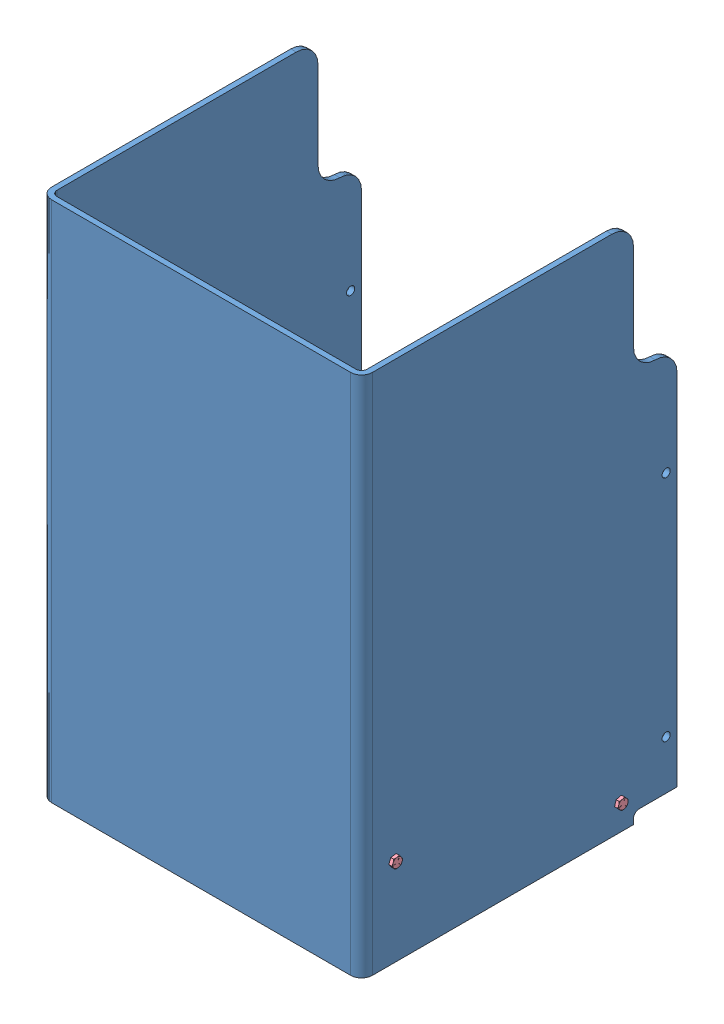
SolidWorks assembly GE-19143, configuration Default. Lengths in mm.
Overall size (382.59 609.6 368.3).
8 component instances, 4 part files, 16 mates.
Components (placement in the parent):
- GE-19144-1: GE-19144 [Default] at origin size (374.65 609.6 368.3)
- GE-19145-3: GE-19145 [Default] at (311.15 103.4321 330.2) x (0 0 1) z (-1 0 0) size (14.66 12.7 361.95)
- GE-19145-4: GE-19145 [Default] at (311.15 30.737 66.675) x (0 -0.158553 0.987351) z (-1 0 0) size (14.66 12.7 361.95)
- GE-19146-1: GE-19146 [Default] at (7.9375 21.7341 10.16) x (0 0.265924 0.963994) z (-1 0 0) size (358.78 3.17 358.78)
- hex_.25_20_.75-1: hex_.25_20_.75 [hex_.25_20_.75] at (7.5406 30.737 66.675) size (23.02 12.83 11.11)
- hex_.25_20_.75-2: hex_.25_20_.75 [hex_.25_20_.75] at (7.5406 103.4321 330.2) x (1 0 0) z (0 -0.158553 0.987351) size (23.02 12.83 11.11)
- hex_.25_20_.75-4: hex_.25_20_.75 [hex_.25_20_.75] at (367.1094 30.737 66.675) x (-1 0 0) z (0 -0.282984 -0.959125) size (23.02 12.83 11.11)
- hex_.25_20_.75-6: hex_.25_20_.75 [hex_.25_20_.75] at (367.1094 103.4321 330.2) x (-1 0 0) z (0 -0.371154 -0.928571) size (23.02 12.83 11.11)
Mates (geometry in assembly coordinates):
- Distance1: distance = 1.5875 mm: plane of GE-19146-1 through (366.7125 24.7948 9.3157) normal (1 0 0); plane of GE-19144-1 through (368.3 609.6 0) normal (-1 0 0)
- Concentric3: concentric: cylinder of GE-19144-1 through (0 30.737 66.675) axis (1 0 0) radius 3.3782; cylinder of hex_.25_20_.75-1 through (0 30.737 66.675) axis (1 0 0) radius 3.175
- Coincident8: coincident: plane of GE-19144-1 through (0 609.6 0) normal (-1 0 0); plane of hex_.25_20_.75-1 through (0 33.9449 72.2313) normal (1 0 0)
- Concentric4: concentric: cylinder of GE-19144-1 through (0 103.4321 330.2) axis (1 0 0) radius 3.3782; cylinder of hex_.25_20_.75-2 through (0 103.4321 330.2) axis (1 0 0) radius 3.175
- Coincident9: coincident: plane of GE-19144-1 through (0 609.6 0) normal (-1 0 0); plane of hex_.25_20_.75-2 through (0 105.7184 336.1946) normal (1 0 0)
- Concentric5: concentric: cylinder of GE-19144-1 through (0 30.737 66.675) axis (1 0 0) radius 3.3782; cylinder of hex_.25_20_.75-4 through (374.65 30.737 66.675) axis (-1 0 0) radius 3.175
- Coincident10: coincident: plane of GE-19144-1 through (374.65 609.6 368.3) normal (1 0 0); plane of hex_.25_20_.75-4 through (374.65 32.2414 60.4381) normal (-1 0 0)
- Concentric6: concentric: cylinder of GE-19144-1 through (0 103.4321 330.2) axis (1 0 0) radius 3.3782; cylinder of hex_.25_20_.75-6 through (374.65 103.4321 330.2) axis (-1 0 0) radius 3.175
- Coincident11: coincident: plane of GE-19144-1 through (374.65 609.6 368.3) normal (1 0 0); plane of hex_.25_20_.75-6 through (374.65 104.3486 323.85) normal (-1 0 0)
- Concentric7: concentric: cylinder of assembly; cylinder of assembly; cylinder of GE-19145-3 through (6.35 103.4321 330.2) axis (1 0 0) radius 2.9337; cylinder of hex_.25_20_.75-6 through (374.65 103.4321 330.2) axis (-1 0 0) radius 3.175
- Coincident12: coincident: plane of GE-19144-1 through (368.3 609.6 0) normal (-1 0 0); plane of GE-19145-3 through (368.3 100.2571 335.6993) normal (1 0 0)
- Concentric8: concentric: cylinder of assembly; cylinder of assembly; cylinder of GE-19145-4 through (6.35 30.737 66.675) axis (1 0 0) radius 2.9337; cylinder of hex_.25_20_.75-4 through (374.65 30.737 66.675) axis (-1 0 0) radius 3.175
- Coincident13: coincident: plane of GE-19144-1 through (368.3 609.6 0) normal (-1 0 0); plane of GE-19145-4 through (368.3 26.7302 71.6013) normal (1 0 0)
- Distance2: distance = 6.35 mm: plane of GE-19146-1 through (7.9375 21.7341 10.16) normal (0 -0.963994 0.265924); cylinder of GE-19144-1 through (0 103.4321 330.2) axis (1 0 0) radius 3.3782
- Distance3: distance = 6.35 mm: plane of GE-19146-1 through (7.9375 21.7341 10.16) normal (0 -0.963994 0.265924); cylinder of GE-19144-1 through (0 30.737 66.675) axis (1 0 0) radius 3.3782
- Distance4: distance = 10.16 mm: line of GE-19144-1; line of GE-19146-1 through (366.7125 21.7341 10.16) axis (-1 0 0)
